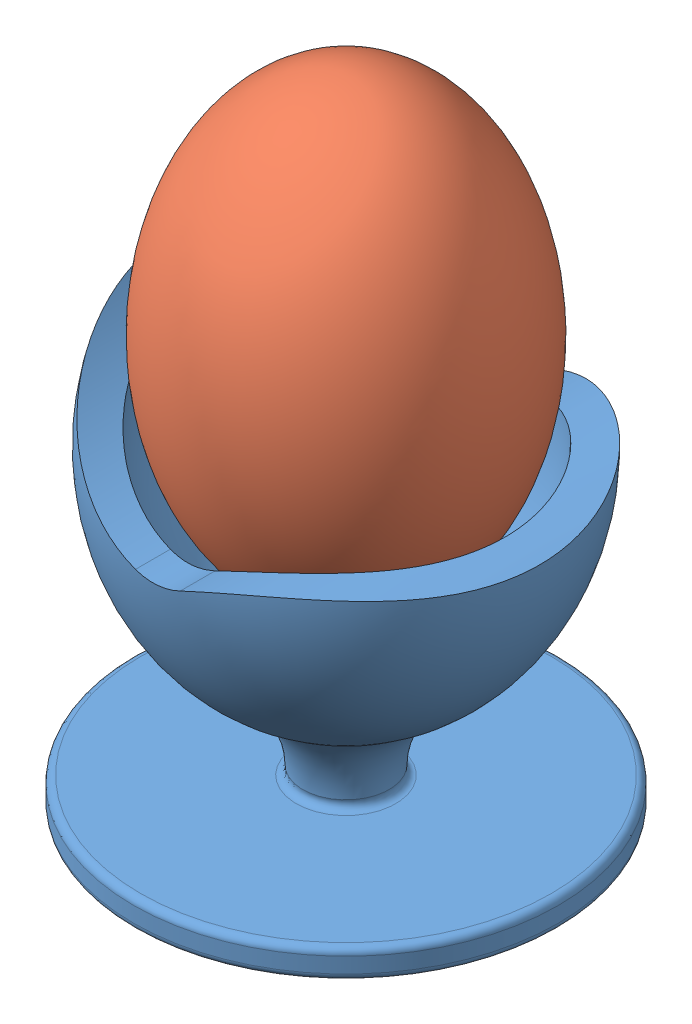
SolidWorks assembly YUMURTA VE YUMURTA KABI, configuration Varsayılan. Lengths in mm.
Overall size (61.41 91.89 61.41).
2 component instances, 2 part files, 2 mates.
Components (placement in the parent):
- yumurta kabı-1: yumurta kabı [Varsayılan] at (-17.7255 3.4493 61.4138) size (61.41 61.51 61.41)
- YUMURTA-1: YUMURTA [Varsayılan] at (-17.7255 17.3806 61.4138) size (45 65 45)
Mates (geometry in assembly coordinates):
- Çakışık1: coincident aligned: plane of yumurta kabı-1 through (-17.7255 3.4493 61.4138) normal (0 0 1); plane of YUMURTA-1 through (-17.7255 17.3806 61.4138) normal (0 0 1)
- Çakışık2: coincident aligned: plane of yumurta kabı-1 through (-17.7255 3.4493 61.4138) normal (1 0 0); plane of YUMURTA-1 through (-17.7255 17.3806 61.4138) normal (1 0 0)
